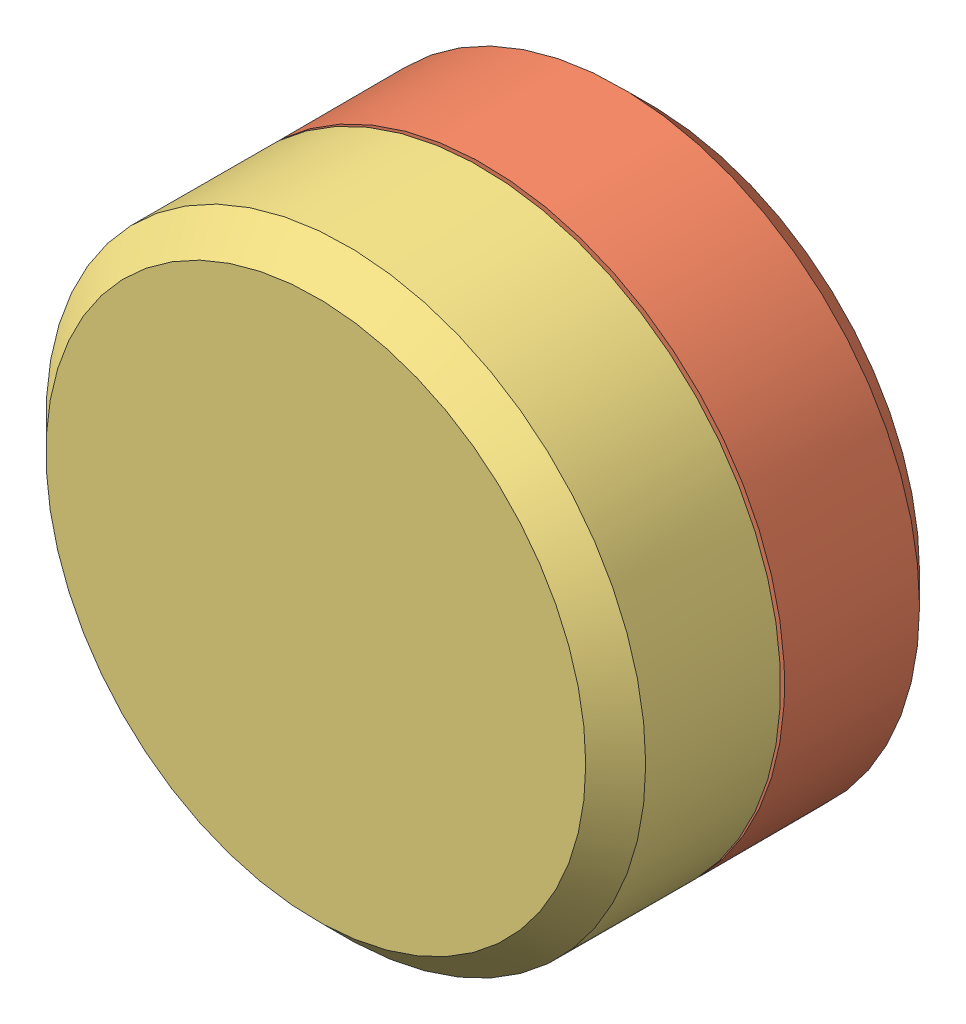
SolidWorks assembly PLANT, configuration Default. Lengths in mm.
Overall size (20 20.25 11.24).
4 component instances, 4 part files, 12 mates.
Components (placement in the parent):
- PCB_Plant-1: PCB_Plant [Default] at origin size (16.15 13.62 9.44)
- bot-1: bot [Default] at (0 0 -6.6307) x (-1 0 0) z (0 0 -1) size (20 20 5.61)
- top-1: top [Default] at (0 0 4.5) x (1 0 0) z (0 0 -1) size (20 20 6.5)
- button-1: button [Default] at (0 0 -1.7307) x (1 0 0) z (0 -1 0) size (7.5 5 2.79)
Mates (geometry in assembly coordinates):
- Coincident1: coincident aligned: plane of PCB_Plant-1 through (0 0 0) normal (0 0 1)
- Coincident2: coincident aligned: plane of PCB_Plant-1 through (0 0 0) normal (0 1 0)
- Coincident3: coincident aligned: plane of PCB_Plant-1 through (0 0 0) normal (1 0 0)
- Concentric1: concentric aligned: cylinder of PCB_Plant-1 through (0 0 -1.6307) axis (0 0 -1) radius 8; cylinder of bot-1 through (0 0 -2.1307) axis (0 0 -1) radius 8.25
- Distance1: distance = 4 mm anti-aligned: plane of bot-1 through (0 0 -5.6307) normal (0 0 1); plane of PCB_Plant-1 through (-6.245 5 -1.6307) normal (0 0 -1)
- Concentric2: concentric anti-aligned: cylinder of PCB_Plant-1 through (0 0 -1.6307) axis (0 0 -1) radius 8; cylinder of top-1 through (0 0 -1) axis (0 0 1) radius 8.25
- Distance2: distance = 3.5 mm anti-aligned: plane of top-1 through (0 0 3.5) normal (0 0 -1); plane of PCB_Plant-1 through (-6.245 5 0) normal (0 0 1)
- Coincident6: coincident aligned: plane of bot-1 through (0 0 -6.6307) normal (0 1 0)
- Coincident7: coincident anti-aligned: plane of top-1 through (0 0 4.5) normal (0 -1 0)
- Concentric3: concentric anti-aligned: cylinder of top-1 through (0 0 -1) axis (0 0 1) radius 10; cylinder of button-1 through (0 0 3.2693) axis (0 0 -1) radius 10.25
- Distance3: distance = 0.4 mm anti-aligned: plane of button-1 through (0 -6.2606 -0.7307) normal (0 0 -1); plane of bot-1 through (0 0 -1.1307) normal (0 0 1)
- Coincident9: coincident anti-aligned: plane of button-1 through (0 0 -1.7307) normal (0 -1 0)
